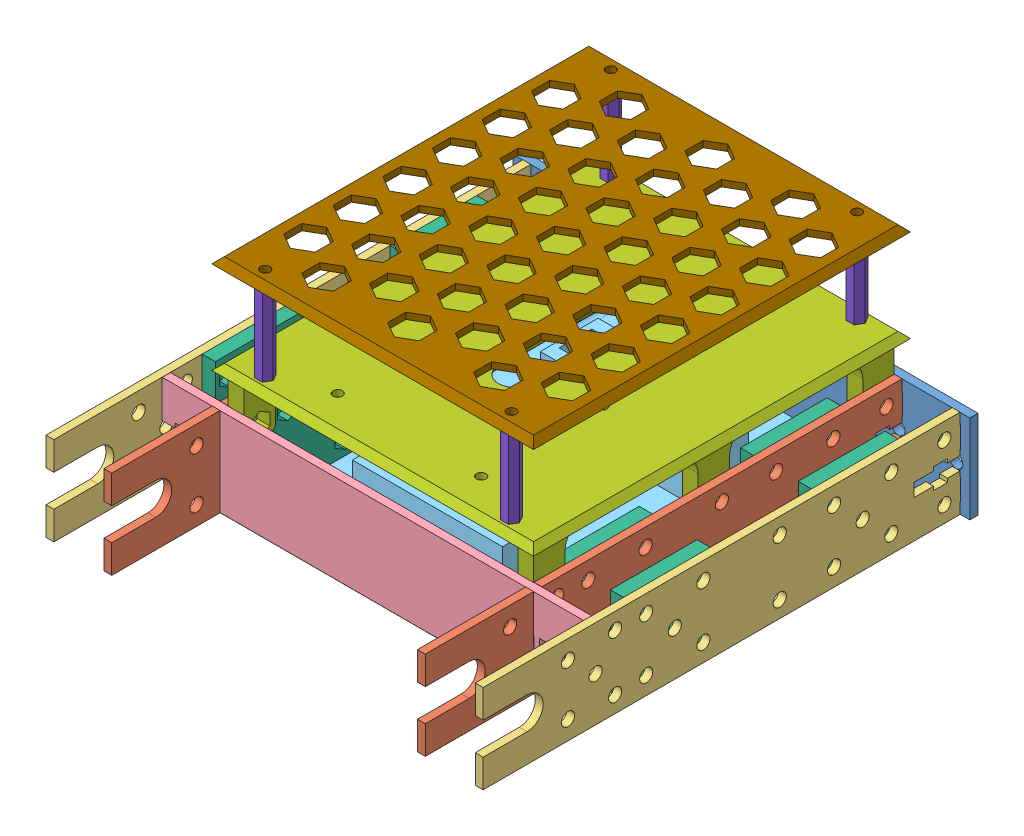
SolidWorks assembly Assem1, configuration Default. Lengths in mm.
Overall size (184.59 90.61 196.34).
21 component instances, 9 part files, 56 mates.
Components (placement in the parent):
- BackBrace-1: BackBrace [Default] at origin size (184.59 35.69 3.3)
- Inner_Sideplate-1: Inner_Sideplate [Default] at (63.3704 0 97.917) size (3.17 35.81 196.34)
- Inner_Sideplate-2: Inner_Sideplate [Default] at (-63.3704 0 97.917) size (3.17 35.81 196.34)
- Outer_Sideplate-1: Outer_Sideplate [Default] at (86.7694 0 97.917) size (3.17 35.81 196.34)
- Outer_Sideplate-2: Outer_Sideplate [Default] at (-86.7694 0 97.917) size (3.17 35.81 196.34)
- MidPlate-1: MidPlate [Default] at (0 0 150.622) x (-1 0 0) z (0 0 1) size (170.36 35.69 3.3)
- Base-2: Base [Default] at (0 -20.3835 76.1365) x (-1 0 0) z (0 0 -1) size (130.05 25.65 152.4)
- Bearing_block-1: Bearing_block [Default] at (-79.8479 0 118.618) x (0 0 1) z (-1 0 0) size (35.05 35.81 5.33)
- Bearing_block-2: Bearing_block [Default] at (-79.8479 0 42.672) x (0 0 1) z (-1 0 0) size (35.05 35.81 5.33)
- Bearing_block-3: Bearing_block [Default] at (-56.4489 0 42.672) x (0 0 1) z (-1 0 0) size (35.05 35.81 5.33)
- Bearing_block-4: Bearing_block [Default] at (-56.4489 0 118.618) x (0 0 1) z (-1 0 0) size (35.05 35.81 5.33)
- Bearing_block-5: Bearing_block [Default] at (56.4489 0 118.618) x (0 0 -1) z (1 0 0) size (35.05 35.81 5.33)
- Bearing_block-6: Bearing_block [Default] at (56.4489 0 42.672) x (0 0 -1) z (1 0 0) size (35.05 35.81 5.33)
- Bearing_block-7: Bearing_block [Default] at (79.8479 0 42.672) x (0 0 1) z (1 0 0) size (35.05 35.81 5.33)
- Bearing_block-8: Bearing_block [Default] at (79.8479 0 118.618) x (0 0 -1) z (1 0 0) size (35.05 35.81 5.33)
- Top-1: Top [Default] at (0 32.893 76.2) x (1 0 0) z (0 0 -1) size (130.05 27.94 152.4)
- Standoff-1: Standoff [Default] at (-49.784 32.893 146.05) x (0.866025 0 0.5) z (-0.5 0 0.866025) size (5.59 40.89 6.45)
- Standoff-2: Standoff [Default] at (49.784 32.893 146.05) x (0.866025 0 0.5) z (-0.5 0 0.866025) size (5.59 40.89 6.45)
- Standoff-3: Standoff [Default] at (49.784 32.893 6.35) x (0.866025 0 0.5) z (-0.5 0 0.866025) size (5.59 40.89 6.45)
- Standoff-4: Standoff [Default] at (-49.784 32.893 6.35) x (0.866025 0 0.5) z (-0.5 0 0.866025) size (5.59 40.89 6.45)
- Lid-1: Lid [Default] at (0 67.691 76.2) size (130.05 2.54 152.4)
Mates (geometry in assembly coordinates):
- Coincident1: coincident aligned: plane of BackBrace-1 through (0 0 0) normal (0 1 0); plane of Inner_Sideplate-1 through (63.3704 0 97.917) normal (0 1 0)
- Coincident2: coincident anti-aligned: plane of BackBrace-1 through (0 0 3.302) normal (0 0 1); plane of Inner_Sideplate-1 through (64.9579 0 3.302) normal (0 0 -1)
- Coincident3: coincident aligned: plane of Inner_Sideplate-1 through (63.3704 0 97.917) normal (1 0 0); plane of assembly through (63.3704 0 0) normal (1 0 0)
- Coincident4: coincident aligned: plane of Inner_Sideplate-2 through (-63.3704 0 97.917) normal (0 1 0); plane of assembly through (0 0 0) normal (0 1 0)
- Coincident6: coincident aligned: plane of Inner_Sideplate-2 through (-63.3704 0 97.917) normal (1 0 0); plane of assembly through (-63.3704 0 0) normal (1 0 0)
- Coincident7: coincident aligned: plane of Outer_Sideplate-1 through (86.7694 0 97.917) normal (0 1 0); plane of assembly through (0 0 0) normal (0 1 0)
- Coincident8: coincident anti-aligned: plane of Outer_Sideplate-1 through (86.7694 0 97.917) normal (1 0 0); plane of assembly through (86.7694 0 0) normal (-1 0 0)
- Coincident10: coincident aligned: plane of Outer_Sideplate-2 through (-86.7694 0 97.917) normal (1 0 0); plane of assembly through (-86.7694 0 0) normal (1 0 0)
- Coincident11: coincident aligned: plane of Outer_Sideplate-2 through (-86.7694 0 97.917) normal (0 1 0); plane of assembly through (0 0 0) normal (0 1 0)
- Coincident12: coincident anti-aligned: plane of Outer_Sideplate-2 through (-85.1819 0 3.302) normal (0 0 -1); plane of BackBrace-1 through (0 0 3.302) normal (0 0 1)
- Coincident13: coincident aligned: plane of MidPlate-1 through (0 0 150.622) normal (0 0 1); plane of assembly through (0 0 150.622) normal (0 0 1)
- Coincident14: coincident anti-aligned: plane of Outer_Sideplate-2 through (-85.1819 0 97.917) normal (1 0 0); plane of MidPlate-1 through (-85.1819 0 152.273) normal (-1 0 0)
- Coincident15: coincident anti-aligned: plane of MidPlate-1; plane of assembly through (0 0 0) normal (0 1 0)
- Coincident19: coincident anti-aligned: plane of BackBrace-1 through (0 0 3.302) normal (0 0 1); plane of Outer_Sideplate-1 through (88.3569 0 3.302) normal (0 0 -1)
- Coincident20: coincident anti-aligned: plane of BackBrace-1 through (0 0 3.302) normal (0 0 1); plane of Inner_Sideplate-2 through (-61.7829 0 3.302) normal (0 0 -1)
- Coincident23: coincident anti-aligned: plane of BackBrace-1 through (92.2939 -17.8435 3.302) normal (0 -1 0); plane of Base-2 through (0 -17.8435 76.1365) normal (0 1 0)
- Coincident24: coincident anti-aligned: plane of Base-2 through (0 -20.3835 76.1365) normal (-1 0 0); plane of assembly through (0 0 0) normal (1 0 0)
- Coincident25: coincident aligned: plane of Base-2 through (0 -20.3835 76.1365) normal (0 0 -1); plane of assembly through (0 0 76.1365) normal (0 0 -1)
- Coincident26: coincident anti-aligned: plane of Outer_Sideplate-2 through (-85.1819 0 97.917) normal (1 0 0); plane of Bearing_block-1 through (-85.1819 0 118.618) normal (-1 0 0)
- Concentric1: concentric aligned: cylinder of Outer_Sideplate-2 through (-85.1819 0 118.618) axis (-1 0 0) radius 2.667; cylinder of Bearing_block-1 through (-79.8479 0 118.618) axis (-1 0 0) radius 2.54
- Concentric2: concentric anti-aligned: cylinder of Outer_Sideplate-2 through (-85.1819 10.795 130.175) axis (-1 0 0) radius 2.667; cylinder of Bearing_block-1 through (-85.1819 10.795 130.175) axis (1 0 0) radius 2.667
- Coincident27: coincident anti-aligned: plane of Outer_Sideplate-2 through (-85.1819 0 97.917) normal (1 0 0); plane of Bearing_block-2 through (-85.1819 0 42.672) normal (-1 0 0)
- Concentric3: concentric aligned: cylinder of Outer_Sideplate-2 through (-85.1819 0 42.672) axis (-1 0 0) radius 2.667; cylinder of Bearing_block-2 through (-79.8479 0 42.672) axis (-1 0 0) radius 2.54
- Concentric4: concentric anti-aligned: cylinder of Outer_Sideplate-2 through (-85.1819 10.795 31.115) axis (-1 0 0) radius 2.667; cylinder of Bearing_block-2 through (-85.1819 10.795 31.115) axis (1 0 0) radius 2.667
- Coincident28: coincident anti-aligned: plane of Inner_Sideplate-2 through (-61.7829 0 97.917) normal (1 0 0); plane of Bearing_block-3 through (-61.7829 0 42.672) normal (-1 0 0)
- Concentric5: concentric aligned: cylinder of Inner_Sideplate-2 through (-61.7829 0 42.672) axis (-1 0 0) radius 2.667; cylinder of Bearing_block-3 through (-56.4489 0 42.672) axis (-1 0 0) radius 2.54
- Concentric6: concentric anti-aligned: cylinder of Inner_Sideplate-2 through (-61.7829 10.795 54.229) axis (-1 0 0) radius 2.667; cylinder of Bearing_block-3 through (-61.7829 10.795 54.229) axis (1 0 0) radius 2.667
- Coincident29: coincident anti-aligned: plane of Inner_Sideplate-2 through (-61.7829 0 97.917) normal (1 0 0); plane of Bearing_block-4 through (-61.7829 0 118.618) normal (-1 0 0)
- Concentric7: concentric aligned: cylinder of Inner_Sideplate-2 through (-61.7829 0 118.618) axis (-1 0 0) radius 2.667; cylinder of Bearing_block-4 through (-56.4489 0 118.618) axis (-1 0 0) radius 2.54
- Concentric8: concentric anti-aligned: cylinder of Inner_Sideplate-2 through (-61.7829 10.795 107.061) axis (-1 0 0) radius 2.667; cylinder of Bearing_block-4 through (-61.7829 10.795 107.061) axis (1 0 0) radius 2.667
- Coincident30: coincident anti-aligned: plane of Inner_Sideplate-1 through (61.7829 0 97.917) normal (-1 0 0); plane of Bearing_block-5 through (61.7829 0 118.618) normal (1 0 0)
- Concentric9: concentric anti-aligned: cylinder of Inner_Sideplate-1 through (64.9579 0 118.618) axis (-1 0 0) radius 2.667; cylinder of Bearing_block-5 through (56.4489 0 118.618) axis (1 0 0) radius 2.54
- Concentric11: concentric aligned: cylinder of Inner_Sideplate-1 through (64.9579 10.795 130.175) axis (-1 0 0) radius 2.667; cylinder of Bearing_block-5 through (61.7829 10.795 130.175) axis (-1 0 0) radius 2.667
- Coincident31: coincident anti-aligned: plane of Inner_Sideplate-1 through (61.7829 0 97.917) normal (-1 0 0); plane of Bearing_block-6 through (61.7829 0 42.672) normal (1 0 0)
- Concentric12: concentric anti-aligned: cylinder of Inner_Sideplate-1 through (64.9579 0 42.672) axis (-1 0 0) radius 2.667; cylinder of Bearing_block-6 through (56.4489 0 42.672) axis (1 0 0) radius 2.54
- Concentric14: concentric aligned: cylinder of Inner_Sideplate-1 through (64.9579 10.795 54.229) axis (-1 0 0) radius 2.667; cylinder of Bearing_block-6 through (61.7829 10.795 54.229) axis (-1 0 0) radius 2.667
- Coincident32: coincident anti-aligned: plane of Outer_Sideplate-1 through (85.1819 0 97.917) normal (-1 0 0); plane of Bearing_block-7 through (85.1819 0 42.672) normal (1 0 0)
- Concentric15: concentric anti-aligned: cylinder of Outer_Sideplate-1 through (88.3569 0 42.672) axis (-1 0 0) radius 2.667; cylinder of Bearing_block-7 through (79.8479 0 42.672) axis (1 0 0) radius 2.54
- Coincident34: coincident anti-aligned: plane of Outer_Sideplate-1 through (85.1819 0 97.917) normal (-1 0 0); plane of Bearing_block-8 through (85.1819 0 118.618) normal (1 0 0)
- Concentric17: concentric anti-aligned: cylinder of Outer_Sideplate-1 through (88.3569 0 118.618) axis (-1 0 0) radius 2.667; cylinder of Bearing_block-8 through (79.8479 0 118.618) axis (1 0 0) radius 2.54
- Concentric19: concentric aligned: cylinder of Outer_Sideplate-1 through (88.3569 10.795 130.175) axis (-1 0 0) radius 2.667; cylinder of Bearing_block-8 through (85.1819 10.795 130.175) axis (-1 0 0) radius 2.667
- Coincident35: coincident aligned: plane of Top-1; plane of assembly through (0 0 0) normal (1 0 0)
- Parallel1: parallel anti-aligned: plane of Top-1 through (0 32.893 76.2) normal (0 -1 0); plane of assembly through (0 0 0) normal (0 1 0)
- Concentric20: concentric anti-aligned: cylinder of Inner_Sideplate-1 through (64.9579 11.303 76.2) axis (-1 0 0) radius 2.667; cylinder of Top-1 through (-65.024 11.303 76.2) axis (1 0 0) radius 2.667
- Concentric21: concentric aligned: cylinder of Outer_Sideplate-1 through (88.3569 10.795 54.229) axis (-1 0 0) radius 2.667; cylinder of Bearing_block-7 through (85.1819 10.795 54.229) axis (-1 0 0) radius 2.667
- Concentric22: concentric aligned: cylinder of Top-1 through (-49.784 4.953 146.05) axis (0 1 0) radius 1.905; cylinder of Standoff-1 through (-49.784 26.797 146.05) axis (0 1 0) radius 1.524
- Coincident36: coincident anti-aligned: plane of Top-1 through (0 32.893 76.2) normal (0 1 0); plane of Standoff-1 through (-49.784 32.893 146.05) normal (0 -1 0)
- Coincident38: coincident anti-aligned: plane of Top-1 through (0 32.893 76.2) normal (0 1 0); plane of Standoff-2 through (49.784 32.893 146.05) normal (0 -1 0)
- Concentric23: concentric aligned: cylinder of Top-1 through (49.784 4.953 146.05) axis (0 1 0) radius 1.905; cylinder of Standoff-2 through (49.784 26.797 146.05) axis (0 1 0) radius 1.524
- Concentric24: concentric aligned: cylinder of Top-1 through (49.784 4.953 6.35) axis (0 1 0) radius 1.905; cylinder of Standoff-3 through (49.784 26.797 6.35) axis (0 1 0) radius 1.524
- Coincident39: coincident anti-aligned: plane of Top-1 through (0 32.893 76.2) normal (0 1 0); plane of Standoff-3 through (49.784 32.893 6.35) normal (0 -1 0)
- Coincident40: coincident anti-aligned: plane of Top-1 through (0 32.893 76.2) normal (0 1 0); plane of Standoff-4 through (-49.784 32.893 6.35) normal (0 -1 0)
- Concentric25: concentric aligned: cylinder of Top-1 through (-49.784 4.953 6.35) axis (0 1 0) radius 1.905; cylinder of Standoff-4 through (-49.784 26.797 6.35) axis (0 1 0) radius 1.524
- Coincident41: coincident anti-aligned: plane of Standoff-1 through (-49.784 67.691 146.05) normal (0 1 0); plane of Lid-1 through (0 67.691 76.2) normal (0 -1 0)
- Coincident42: coincident aligned: plane of Lid-1 through (0 67.691 76.2) normal (1 0 0); plane of assembly through (0 0 0) normal (1 0 0)
- Concentric26: concentric aligned: cylinder of Standoff-1 through (-49.784 61.595 146.05) axis (0 1 0) radius 1.524; cylinder of Lid-1 through (-49.784 67.691 146.05) axis (0 1 0) radius 1.905
